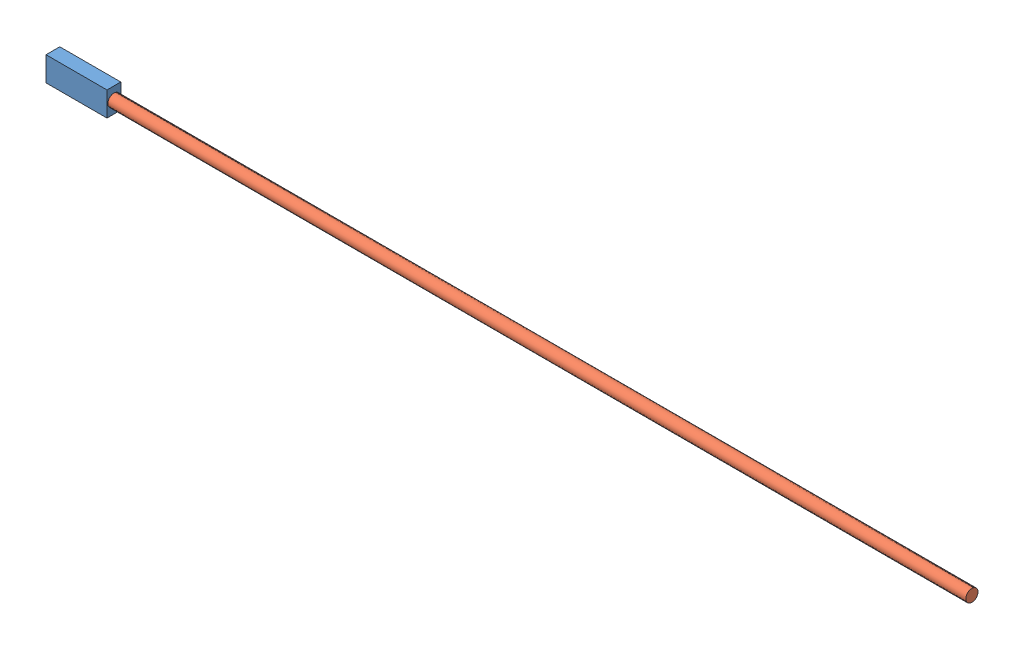
SolidWorks assembly Harness_9-CABLE_HARNESSING_ASSEMBLY, configuration AnnotateFlattenedRoute1 - Default. Lengths in mm.
Overall size (150.69 4 2.26).
3 component instances, 3 part files, 1 mates.
Components (placement in the parent):
- 01_PIN_CONNECTOR-1: 01_PIN_CONNECTOR [Default] at (-10 2 -1.125) x (0 0 1) z (1 0 0)
- Cable^Harness_9-CABLE_HARNESSING_ASSEMBLY-1: Cable^Harness_9-CABLE_HARNESSING_ASSEMBLY [Default] at origin (suppressed, hidden, virtual)
- Flattened_Cable^Harness_9-CABLE_HARNESSING_ASSEMBLY-1: Flattened_Cable^Harness_9-CABLE_HARNESSING_ASSEMBLY [Default] at origin (virtual)
Mates (geometry in assembly coordinates):
- Coincident98: coincident anti-aligned: plane of STACK_SHELVES-2/FAKE_PCB-4 through (89.4838 145.9 -84.8747) normal (0 1 0); plane of 01_PIN_CONNECTOR-1 through (38.5303 145.9 -42.8883) normal (0 -1 0)
